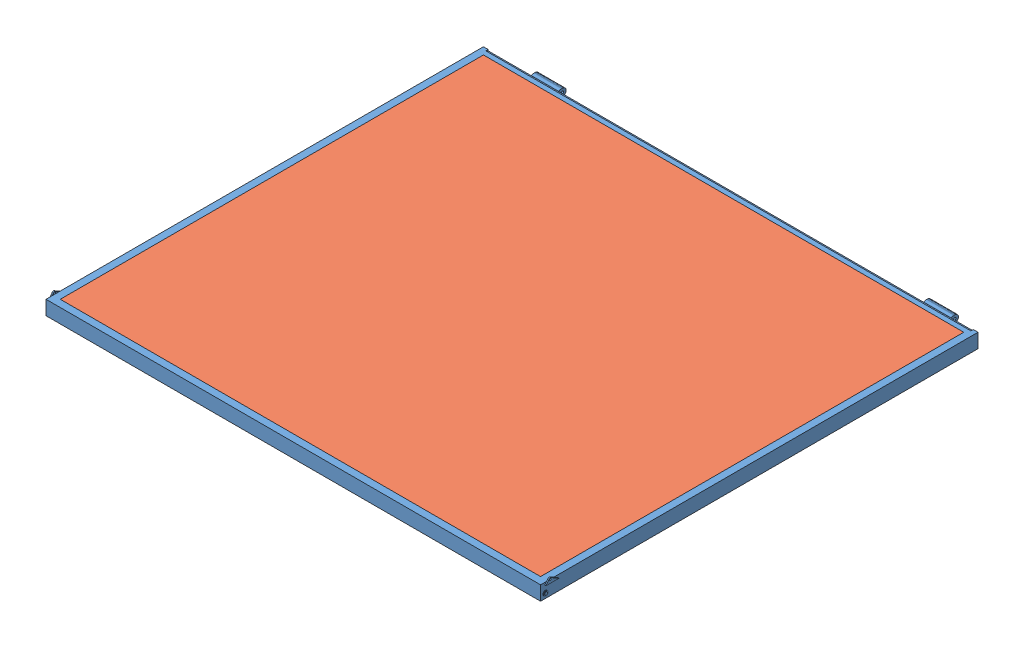
SolidWorks assembly CANTILEVER_ASSEMBLY, configuration Default. Lengths in mm.
Overall size (2654.3 114.3 2432.16).
3 component instances, 3 part files, 6 mates.
Components (placement in the parent):
- CANTILEVER_FLOOR FRAME-1: CANTILEVER_FLOOR FRAME [Default] at (40.1663 1548.6124 2442.5351) size (2654.3 114.3 2432.16)
- wood_floor-1: wood_floor [Default] at (40.1663 1574.0124 2442.5351) size (2565.4 12.7 2260.35)
- CANTILEVER_INSULATION_100X90.5X2.5-1: CANTILEVER_INSULATION_100X90.5X2.5 [Default] at (40.1663 1510.5124 2442.5351) x (0 0 -1) z (1 0 0) size (2260.35 63.5 2565.4)
Mates (geometry in assembly coordinates):
- Coincident2: coincident anti-aligned: plane of CANTILEVER_FLOOR FRAME-1 through (-1242.5337 1586.7124 1272.2571) normal (1 0 0); plane of wood_floor-1 through (-1242.5337 1586.7124 3572.7081) normal (-1 0 0)
- Coincident3: coincident anti-aligned: plane of CANTILEVER_FLOOR FRAME-1 through (-1282.6387 1586.7124 3572.7081) normal (0 0 -1); plane of wood_floor-1 through (-1242.5337 1586.7124 3572.7081) normal (0 0 1)
- Coincident7: coincident anti-aligned: plane of wood_floor-1 through (40.1663 1574.0124 2442.5351) normal (0 -1 0); plane of CANTILEVER_INSULATION_100X90.5X2.5-1 through (40.1663 1574.0124 2442.5351) normal (0 1 0)
- Coincident8: coincident anti-aligned: plane of CANTILEVER_FLOOR FRAME-1 through (-1282.6387 1586.7124 3572.7081) normal (0 0 -1); plane of CANTILEVER_INSULATION_100X90.5X2.5-1 through (-1242.5337 1574.0124 3572.7081) normal (0 0 1)
- Coincident9: coincident anti-aligned: plane of CANTILEVER_FLOOR FRAME-1 through (1322.8663 1586.7124 3612.8131) normal (-1 0 0); plane of CANTILEVER_INSULATION_100X90.5X2.5-1 through (1322.8663 1574.0124 3572.7081) normal (1 0 0)
- Coincident10: coincident aligned: plane of CANTILEVER_FLOOR FRAME-1 through (1322.8663 1586.7124 3612.8131) normal (0 1 0); plane of wood_floor-1 through (40.1663 1586.7124 2442.5351) normal (0 1 0)
